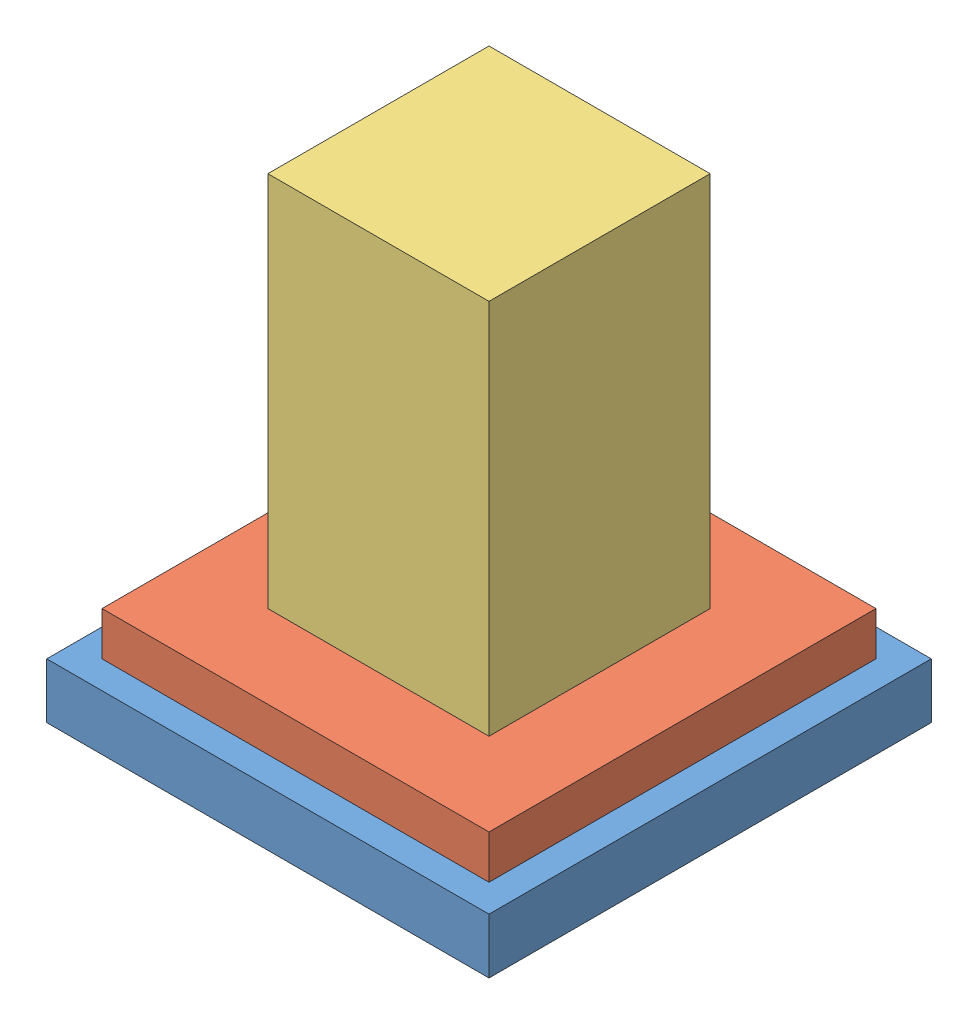
SolidWorks assembly lec41, configuration Default. Lengths in mm.
Overall size (101.6 109.22 101.6).
3 component instances, 3 part files, 4 mates.
Components (placement in the parent):
- Base-1: Base [Default] at (40.3068 38.3558 82.3784) size (101.6 12.7 101.6)
- Middle Block-1: Middle Block [Default] at (40.3068 51.0558 82.3784) size (88.9 10 88.9)
- Rod-1: Rod [Default] at (40.3068 45.9758 82.3784) size (50.8 101.6 50.8)
Mates (geometry in assembly coordinates):
- ProfileCenter1: profile center anti-aligned: plane of Base-1 through (40.3068 51.0558 82.3784) normal (0 1 0); plane of Middle Block-1 through (40.3068 51.0558 82.3784) normal (0 -1 0)
- Coincident1: coincident anti-aligned: plane of Base-1 through (40.3068 45.9758 82.3784) normal (0 1 0); plane of Rod-1 through (40.3068 45.9758 82.3784) normal (0 -1 0)
- Coincident2: coincident anti-aligned: plane of Middle Block-1 through (14.9068 51.0548 56.9784) normal (1 0 0); plane of Rod-1 through (14.9068 147.5758 56.9784) normal (-1 0 0)
- Coincident3: coincident anti-aligned: plane of Middle Block-1 through (65.7068 51.0548 56.9784) normal (0 0 1); plane of Rod-1 through (65.7068 147.5758 56.9784) normal (0 0 -1)
